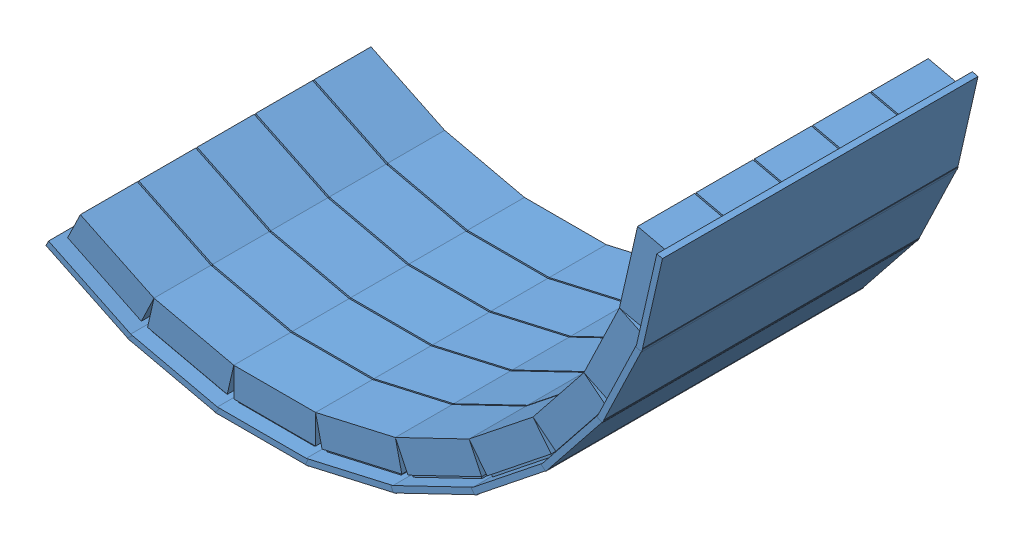
SolidWorks assembly CshapedDetectorid, configuration Default. Lengths in mm.
Overall size (527.59 312.86 270).
9 component instances, 1 part files, 26 mates.
Components (placement in the parent):
- 5Detector-1: 5Detector [Default] at (91.8512 126.8436 184.2598) size (80 32 270)
- 5Detector-2: 5Detector [Default] at (168.0955 135.4362 184.2598) x (0.974917 0.22257 0) z (0 0 1) size (80 32 270)
- 5Detector-4: 5Detector [Default] at (240.515 160.783 184.2598) x (0.900926 0.433974 0) z (0 0 1) size (80 32 270)
- 5Detector-5: 5Detector [Default] at (305.4764 201.6123 184.2598) x (0.781738 0.623607 0) z (0 0 1) size (80 32 270)
- 5Detector-6: 5Detector [Default] at (359.7211 255.8759 184.2598) x (0.623334 0.781956 0) z (0 0 1) size (80 32 270)
- 5Detector-7: 5Detector [Default] at (400.5278 320.8517 184.2598) x (0.433659 0.901077 0) z (0 0 1) size (80 32 270)
- 5Detector-8: 5Detector [Default] at (15.6069 135.4362 184.2598) x (0.974917 -0.22257 0) z (0 0 1) size (80 32 270)
- 5Detector-9: 5Detector [Default] at (-56.8125 160.783 184.2598) x (0.900926 -0.433974 0) z (0 0 1) size (80 32 270)
- 5Detector-10: 5Detector [Default] at (425.8492 393.2799 184.2598) x (0.222229 0.974994 0) z (0 0 1) size (80 32 270)
Mates (geometry in assembly coordinates):
- Coincident2: coincident anti-aligned: line of 5Detector-1 through (126.8512 158.8436 308.2693) axis (0 0 -1); line of 5Detector-2 through (126.8512 158.8436 259.5203) axis (0 0 1)
- Parallel1: parallel anti-aligned: line of 5Detector-1 through (126.8512 158.8436 308.2693) axis (0 0 -1); line of 5Detector-2 through (126.8512 158.8436 259.5203) axis (0 0 1)
- Angle6: planar angle = 2.917143 rad anti-aligned: line of 5Detector-2 through (126.8512 158.8436 308.2693) axis (0.974917 0.22257 0); line of 5Detector-1 through (56.8512 158.8436 308.2693) axis (1 0 0)
- Coincident12: coincident: line of 5Detector-1 through (126.8512 158.8436 308.2693) axis (0 0 -1); plane of 5Detector-2 through (160.9733 166.6336 184.2598) normal (-0.22257 0.974917 0)
- Coincident19: coincident anti-aligned: line of 5Detector-2 through (195.0954 174.4235 308.2693) axis (0 0 -1); line of 5Detector-4 through (195.0954 174.4235 259.5203) axis (0 0 1)
- Coincident22: coincident: point of 5Detector-1; point of 5Detector-2
- Angle9: planar angle = 2.917143 rad anti-aligned: line of 5Detector-4 through (195.0954 174.4235 308.2693) axis (0.900926 0.433974 0); line of 5Detector-2 through (126.8512 158.8436 308.2693) axis (0.974917 0.22257 0)
- Coincident24: coincident: point of 5Detector-2; point of 5Detector-4
- Coincident25: coincident anti-aligned: line of 5Detector-4 through (258.1602 204.8017 308.2693) axis (0 0 -1); line of 5Detector-5 through (258.1602 204.8017 259.5203) axis (0 0 1)
- Angle10: planar angle = 2.917143 rad anti-aligned: line of 5Detector-5 through (258.1602 204.8017 308.2693) axis (0.781738 0.623607 0); line of 5Detector-4 through (195.0954 174.4235 308.2693) axis (0.900926 0.433974 0)
- Coincident27: coincident: point of 5Detector-4; point of 5Detector-5
- Coincident28: coincident anti-aligned: line of 5Detector-5 through (312.8819 248.4541 308.2693) axis (0 0 -1); line of 5Detector-6 through (312.8819 248.4541 259.5203) axis (0 0 1)
- Angle11: planar angle = 2.917143 rad anti-aligned: line of 5Detector-6 through (312.8819 248.4541 308.2693) axis (0.623334 0.781956 0); line of 5Detector-5 through (258.1602 204.8017 308.2693) axis (0.781738 0.623607 0)
- Coincident30: coincident: point of 5Detector-5; point of 5Detector-6
- Coincident31: coincident: line of 5Detector-6 through (356.5152 303.191 308.2693) axis (0 0 -1); line of 5Detector-7 through (356.5152 303.191 259.5203) axis (0 0 1)
- Angle12: planar angle = 2.917143 rad: line of 5Detector-6 through (312.8819 248.4541 308.2693) axis (0.623334 0.781956 0); line of 5Detector-7 through (356.5152 303.191 308.2693) axis (0.433659 0.901077 0)
- Coincident33: coincident: point of 5Detector-6; point of 5Detector-7
- Coincident34: coincident: line of 5Detector-1 through (56.8512 158.8436 259.5203) axis (0 0 1); line of 5Detector-8 through (56.8512 158.8436 308.2693) axis (0 0 -1)
- Angle13: planar angle = 2.917143 rad: line of 5Detector-1 through (56.8512 158.8436 308.2693) axis (1 0 0); line of 5Detector-8 through (-11.393 174.4235 308.2693) axis (0.974917 -0.22257 0)
- Coincident36: coincident: point of 5Detector-1; point of 5Detector-8
- Coincident37: coincident: line of 5Detector-8 through (-11.393 174.4235 259.5203) axis (0 0 1); line of 5Detector-9 through (-11.393 174.4235 308.2693) axis (0 0 -1)
- Angle14: planar angle = 2.917143 rad: line of 5Detector-9 through (-74.4577 204.8017 308.2693) axis (0.900926 -0.433974 0); line of 5Detector-8 through (-11.393 174.4235 308.2693) axis (0.974917 -0.22257 0)
- Coincident39: coincident: point of 5Detector-8; point of 5Detector-9
- Coincident40: coincident: line of 5Detector-7 through (386.8714 366.2664 308.2693) axis (0 0 -1); line of 5Detector-10 through (386.8714 366.2664 259.5203) axis (0 0 1)
- Angle15: planar angle = 2.917143 rad: line of 5Detector-10 through (386.8714 366.2664 308.2693) axis (0.222229 0.974994 0); line of 5Detector-7 through (356.5152 303.191 308.2693) axis (0.433659 0.901077 0)
- Coincident42: coincident: point of 5Detector-7; point of 5Detector-10
